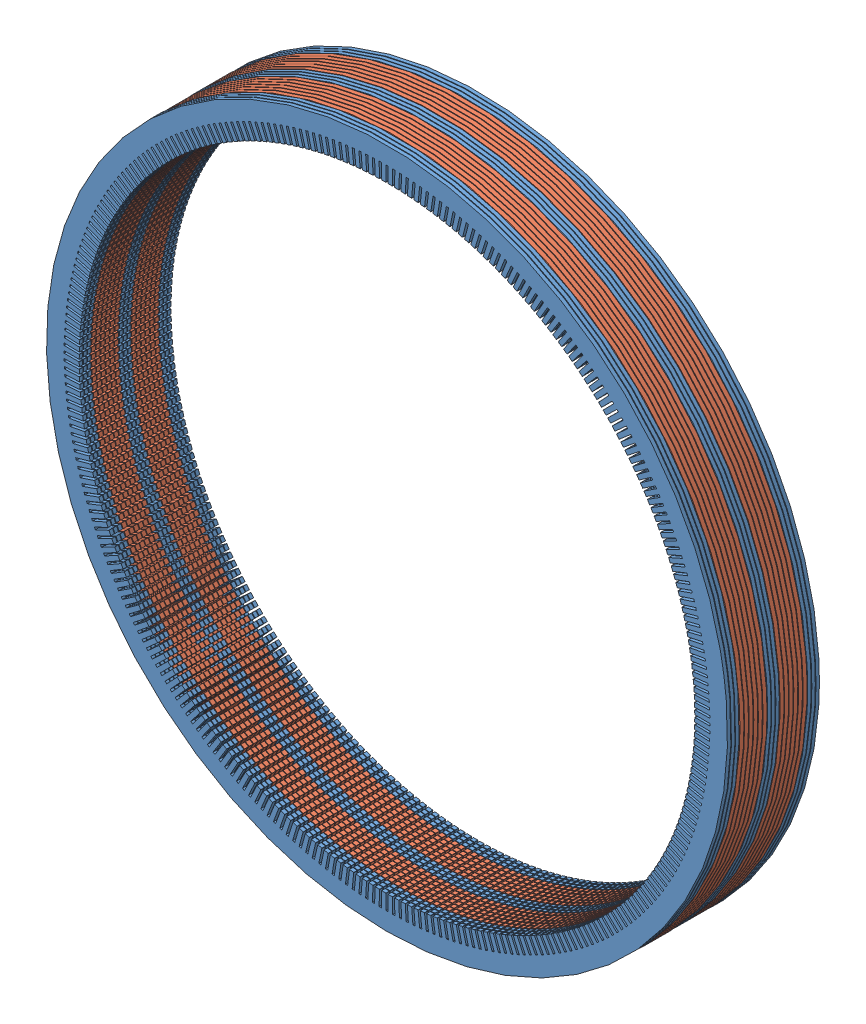
SolidWorks assembly StatorWithDuctsAndWedge, configuration Default. Lengths in mm.
Overall size (7786.27 7786.27 925).
21 component instances, 2 part files, 16 mates.
Components (placement in the parent):
- LamStack35mmWithWedge-1: LamStack35mmWithWedge [Default] at (1823.9573 3643.6405 5590.9551) size (6858 6858 35)
- LamStack35mmWithWedge-2: LamStack35mmWithWedge [Default] at (1823.9573 3643.6405 5632.4551) size (6858 6858 35)
- LamStack35mmWithWedge-3: LamStack35mmWithWedge [Default] at (1823.9573 3643.6405 5673.9551) size (6858 6858 35)
- LamStack40mmWithWedge-1: LamStack40mmWithWedge [Default] at (1823.9573 3643.6405 5715.4551) x (0.999781 0.020942 0) z (0 0 1) size (6858 6858 40)
- LamStack40mmWithWedge-2: LamStack40mmWithWedge [Default] at (1823.9573 3643.6405 5761.9551) x (0.999781 0.020942 0) z (0 0 1) size (6858 6858 40)
- LamStack40mmWithWedge-3: LamStack40mmWithWedge [Default] at (1823.9573 3643.6405 5808.4551) x (0.999781 0.020942 0) z (0 0 1) size (6858 6858 40)
- LamStack40mmWithWedge-4: LamStack40mmWithWedge [Default] at (1823.9573 3643.6405 5854.9551) x (0.999781 0.020942 0) z (0 0 1) size (6858 6858 40)
- LamStack40mmWithWedge-5: LamStack40mmWithWedge [Default] at (1823.9573 3643.6405 5901.4551) x (0.999781 0.020942 0) z (0 0 1) size (6858 6858 40)
- LamStack40mmWithWedge-6: LamStack40mmWithWedge [Default] at (1823.9573 3643.6405 5947.9551) x (0.999781 0.020942 0) z (0 0 1) size (6858 6858 40)
- LamStack35mmWithWedge-4: LamStack35mmWithWedge [Default] at (1823.9573 3643.6405 5994.4551) x (0.999781 0.020942 0) z (0 0 1) size (6858 6858 35)
- LamStack35mmWithWedge-5: LamStack35mmWithWedge [Default] at (1823.9573 3643.6405 6035.9551) x (0.999781 0.020942 0) z (0 0 1) size (6858 6858 35)
- LamStack35mmWithWedge-6: LamStack35mmWithWedge [Default] at (1823.9573 3643.6405 6077.4551) x (0.999781 0.020942 0) z (0 0 1) size (6858 6858 35)
- LamStack40mmWithWedge-7: LamStack40mmWithWedge [Default] at (1823.9573 3643.6405 6118.9551) size (6858 6858 40)
- LamStack40mmWithWedge-8: LamStack40mmWithWedge [Default] at (1823.9573 3643.6405 6165.4551) size (6858 6858 40)
- LamStack40mmWithWedge-9: LamStack40mmWithWedge [Default] at (1823.9573 3643.6405 6211.9551) size (6858 6858 40)
- LamStack40mmWithWedge-10: LamStack40mmWithWedge [Default] at (1823.9573 3643.6405 6258.4551) size (6858 6858 40)
- LamStack40mmWithWedge-11: LamStack40mmWithWedge [Default] at (1823.9573 3643.6405 6304.9551) size (6858 6858 40)
- LamStack40mmWithWedge-12: LamStack40mmWithWedge [Default] at (1823.9573 3643.6405 6351.4551) size (6858 6858 40)
- LamStack35mmWithWedge-7: LamStack35mmWithWedge [Default] at (1823.9573 3643.6405 6397.9551) x (0.989272 0.146083 0) z (0 0 1) size (6858 6858 35)
- LamStack35mmWithWedge-8: LamStack35mmWithWedge [Default] at (1823.9573 3643.6405 6439.4551) x (0.989272 0.146083 0) z (0 0 1) size (6858 6858 35)
- LamStack35mmWithWedge-9: LamStack35mmWithWedge [Default] at (1823.9573 3643.6405 6480.9551) x (0.989272 0.146083 0) z (0 0 1) size (6858 6858 35)
Mates (geometry in assembly coordinates):
- Parallel1: parallel anti-aligned: plane of LamStack35mmWithWedge-3 through (1823.9573 3643.6405 5708.9551) normal (0 0 1); plane of LamStack40mmWithWedge-1 through (1823.9573 3643.6405 5715.4551) normal (0 0 -1)
- Concentric1: concentric aligned: circle of LamStack35mmWithWedge-3; circle of LamStack40mmWithWedge-1
- Distance1: distance = 6.5 mm anti-aligned: plane of LamStack40mmWithWedge-1 through (1823.9573 3643.6405 5715.4551) normal (0 0 -1); plane of LamStack35mmWithWedge-3 through (1823.9573 3643.6405 5708.9551) normal (0 0 1)
- Coincident6: coincident aligned: line of LamStack35mmWithWedge-3 through (-984.5867 2334.1971 5708.9551) axis (0 0 -1); line of LamStack40mmWithWedge-1 through (-984.5867 2334.1971 5755.4551) axis (0 0 -1)
- Parallel2: parallel anti-aligned: plane of LamStack40mmWithWedge-6 through (1823.9573 3643.6405 5987.9551) normal (0 0 1); plane of LamStack35mmWithWedge-4 through (1823.9573 3643.6405 5994.4551) normal (0 0 -1)
- Concentric2: concentric aligned: circle of LamStack40mmWithWedge-6; circle of LamStack35mmWithWedge-4
- Distance2: distance = 6.5 mm anti-aligned: plane of LamStack35mmWithWedge-4 through (1823.9573 3643.6405 5994.4551) normal (0 0 -1); plane of LamStack40mmWithWedge-6 through (1823.9573 3643.6405 5987.9551) normal (0 0 1)
- Coincident10: coincident aligned: line of LamStack40mmWithWedge-6 through (-528.9919 1627.1604 5987.9551) axis (0 0 -1); line of LamStack35mmWithWedge-4 through (-528.9919 1627.1604 6029.4551) axis (0 0 -1)
- Parallel3: parallel anti-aligned: plane of LamStack35mmWithWedge-6 through (1823.9573 3643.6405 6112.4551) normal (0 0 1); plane of LamStack40mmWithWedge-7 through (1823.9573 3643.6405 6118.9551) normal (0 0 -1)
- Concentric3: concentric aligned: circle of LamStack35mmWithWedge-6; circle of LamStack40mmWithWedge-7
- Distance3: distance = 6.5 mm anti-aligned: plane of LamStack40mmWithWedge-7 through (1823.9573 3643.6405 6118.9551) normal (0 0 -1); plane of LamStack35mmWithWedge-6 through (1823.9573 3643.6405 6112.4551) normal (0 0 1)
- Coincident14: coincident aligned: line of LamStack35mmWithWedge-6 through (2583.9382 639.4783 6112.4551) axis (0 0 -1); line of LamStack40mmWithWedge-7 through (2583.9382 639.4783 6158.9551) axis (0 0 -1)
- Concentric4: concentric aligned: circle of LamStack40mmWithWedge-12; circle of LamStack35mmWithWedge-7
- Parallel4: parallel anti-aligned: plane of LamStack40mmWithWedge-12 through (1823.9573 3643.6405 6391.4551) normal (0 0 1); plane of LamStack35mmWithWedge-7 through (1823.9573 3643.6405 6397.9551) normal (0 0 -1)
- Distance4: distance = 6.5 mm anti-aligned: plane of LamStack35mmWithWedge-7 through (1823.9573 3643.6405 6397.9551) normal (0 0 -1); plane of LamStack40mmWithWedge-12 through (1823.9573 3643.6405 6391.4551) normal (0 0 1)
- Coincident18: coincident aligned: line of LamStack40mmWithWedge-12 through (553.5207 817.2378 6391.4551) axis (0 0 -1); line of LamStack35mmWithWedge-7 through (553.5207 817.2378 6432.9551) axis (0 0 -1)
